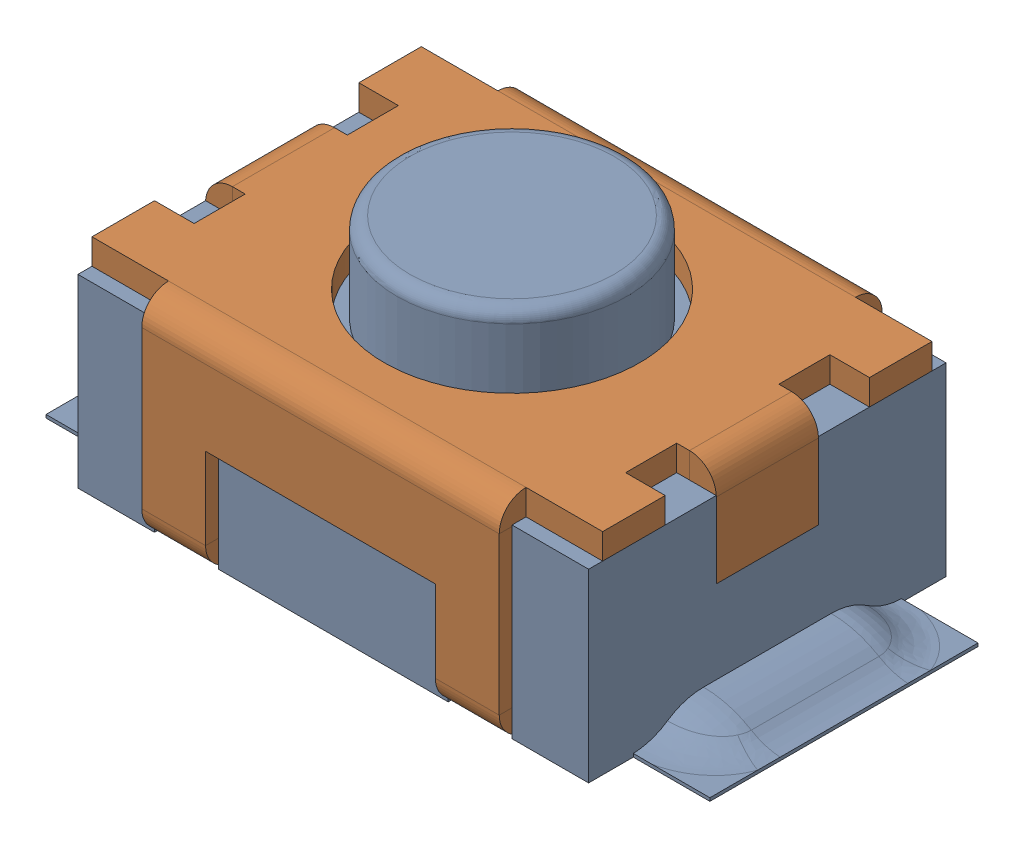
SolidWorks assembly User Library-ARDUINO_MINI_V1_button_reset_1, configuration Default. Lengths in mm.
Overall size (5.2 2.15 3).
2 component instances, 2 part files, 0 mates.
Components (placement in the parent):
- User Library-ARDUINO_MINI_V1_reset core-1: User Library-ARDUINO_MINI_V1_reset core [Default] at origin size (5.2 2.15 2.8)
- User Library-ARDUINO_MINI_V1_reset shell-1: User Library-ARDUINO_MINI_V1_reset shell [Default] at (0 1.65 0) x (0 0 1) z (-1 0 0) size (3 1.65 4)
